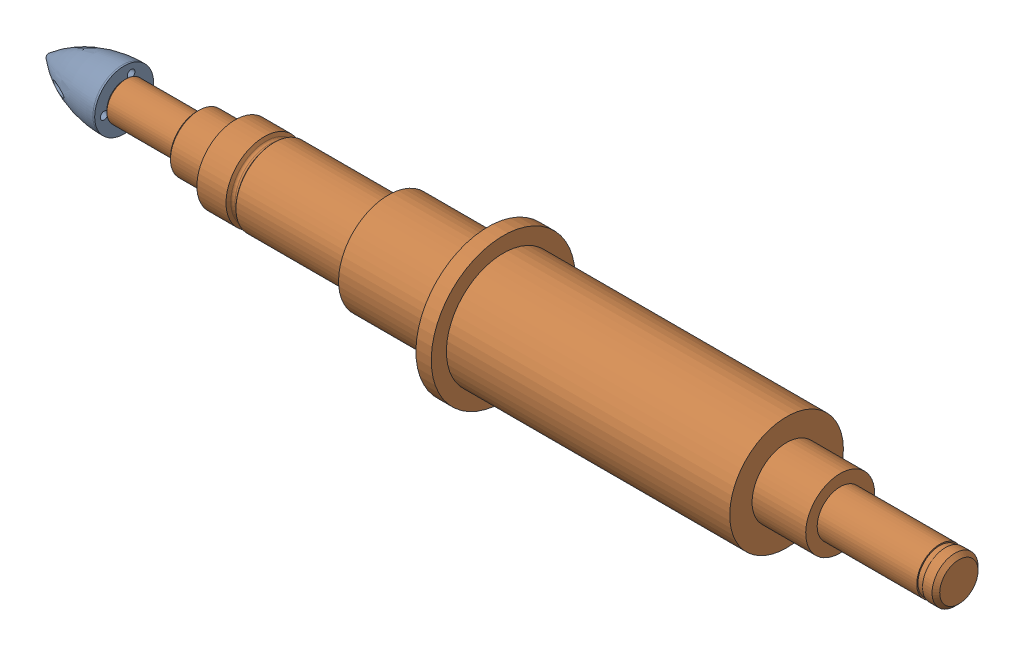
SolidWorks assembly Shaft-Model-Reduced, configuration Default. Lengths in mm.
Overall size (120 23.26 23.26).
3 component instances, 3 part files, 5 mates.
Components (placement in the parent):
- Impeller_LOX-1: Impeller_LOX [Standard] at (-13.3167 24.8871 3.6809) (suppressed, hidden)
- Impeller-Nut-1: Impeller-Nut [Default] at (0 2.4895 2.9368) x (1 0 0) z (0 0.343024 0.939326) size (16 7.7 7.7)
- Shaft-1: Shaft [Default] at (49.5 2.4895 2.9368) x (1 0 0) z (0 -0.276459 -0.961026) size (110 18.8 18.8)
Mates (geometry in assembly coordinates):
- Tangent1: tangent: torus of Impeller-Nut-1
- Coincident1: coincident aligned: plane of Impeller-Nut-1 through (0 6.1059 1.6162) normal (1 0 0)
- Concentric1: concentric: cylinder of Impeller-Nut-1 through (-88.99 2.4895 2.9368) axis (-1 0 0) radius 1.5; cylinder of Shaft-1 through (0 2.4895 2.9368) axis (-1 0 0) radius 1.25
- Coincident2: coincident: plane of Impeller-Nut-1 through (0 6.1059 1.6162) normal (1 0 0); plane of Shaft-1 through (0 0.3272 3.5589) normal (-1 0 0)
- Lock1: lock: unknown of Impeller-Nut-1; unknown of Shaft-1
